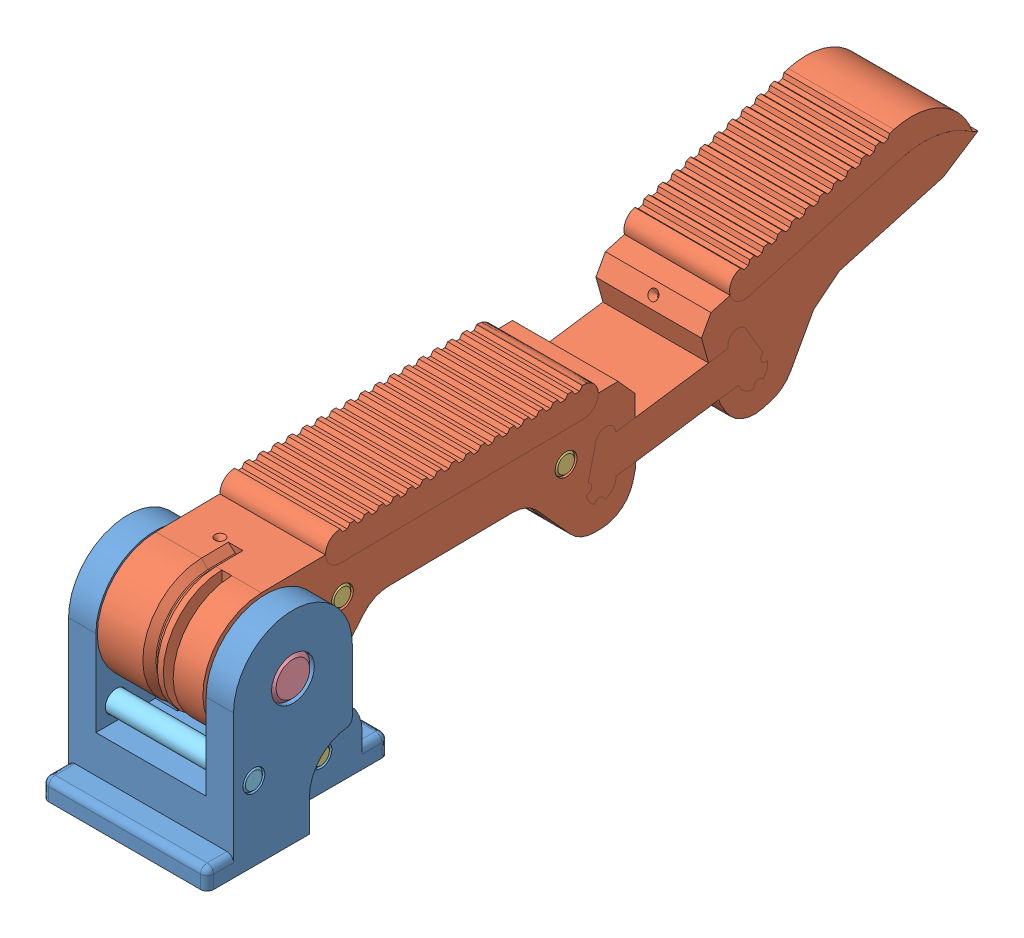
SolidWorks assembly block_finger_pf_t, configuration Default. Lengths in mm.
Overall size (25.4 45.69 121.76).
10 component instances, 8 part files, 18 mates.
Components (placement in the parent):
- c1_t-1: c1_t [Default] at origin size (25 30.67 32)
- t_pf-1: t_pf [Default] at (-0.15 21.67 -14.7858) x (1 0 0) z (0 -0.013363 0.999911) size (16 29.93 117.65)
- 98381A472 D1-8 L5-8-1: 98381A472 D1-8 L5-8 [98381A472] at (-0.0875 23.995 -26.9308) size (15.88 3.17 3.17)
- 98381A472 D1-8 L5-8-2: 98381A472 D1-8 L5-8 [98381A472] at (-0.0875 24.448 -60.8289) size (15.88 3.17 3.17)
- 98381A542 D1-4 L1-1: 98381A542 D1-4 L1 [98381A542] at (-0.2 21.67 -14.7858) size (25.4 6.35 6.35)
- 98381A475 D1-8 L1-1: 98381A475 D1-8 L1 [98381A475] at (-0.2 11.2575 -8.8732) size (25.4 3.17 3.17)
- 98381A472 D1-8 L5-8-3: 98381A472 D1-8 L5-8 [98381A472] at (0.0625 4.925 -23.535) size (15.88 3.17 3.17)
- 93365A120 4-40 insert-1: 93365A120 4-40 insert [93365A120] at (-0.15 27.5639 -100.2943) x (1 0 0) z (0 0.622567 -0.782567) size (4.37 3.82 4.37)
- 91253A106 4-40 L1-4 countersunk-1: 91253A106 4-40 L1-4 countersunk [91253A106] at (-0.15 25.9039 -101.6148) x (1 0 0) z (0 -0.782567 -0.622567) size (6.48 6.48 6.63)
- 3434T31 - nylon pulley-1: 3434T31 - nylon pulley [Default] at (-0.15 4.925 -23.535) x (0 -0.840446 -0.541896) z (0 -0.541896 0.840446) size (9.5 2.4 9.5)
Mates (geometry in assembly coordinates):
- Concentric1: concentric: cylinder of c1_t-1 through (-12.5 21.67 -14.7858) axis (1 0 0) radius 3.25; cylinder of 98381A542 D1-4 L1-1 through (-12.9 21.67 -14.7858) axis (1 0 0) radius 3.175
- Coincident1: coincident: plane of c1_t-1 through (12.5 21.67 -14.7858) normal (1 0 0); plane of 98381A542 D1-4 L1-1 through (12.5 21.67 -14.7858) normal (1 0 0)
- Concentric2: concentric: cylinder of t_pf-1 through (-8.15 21.67 -14.7858) axis (1 0 0) radius 3.35; cylinder of 98381A542 D1-4 L1-1 through (-12.9 21.67 -14.7858) axis (1 0 0) radius 3.175
- Distance1: distance = 0.2 mm: plane of c1_t-1 through (-8.35 21.67 -14.7858) normal (1 0 0); plane of t_pf-1 through (-8.15 21.67 -14.7858) normal (-1 0 0)
- Concentric3: concentric: cylinder of t_pf-1 through (-8.15 23.995 -26.9308) axis (1 0 0) radius 1.6625; cylinder of 98381A472 D1-8 L5-8-1 through (-8.025 23.995 -26.9308) axis (1 0 0) radius 1.5875
- Coincident3: coincident: plane of t_pf-1 through (7.85 21.67 -14.7858) normal (1 0 0); plane of 98381A472 D1-8 L5-8-1 through (7.85 23.995 -26.9308) normal (1 0 0)
- Concentric4: concentric: cylinder of t_pf-1 through (-8.15 24.448 -60.8289) axis (1 0 0) radius 1.6625; cylinder of 98381A472 D1-8 L5-8-2 through (-8.025 24.448 -60.8289) axis (1 0 0) radius 1.5875
- Coincident4: coincident: plane of t_pf-1 through (7.85 21.67 -14.7858) normal (1 0 0); plane of 98381A472 D1-8 L5-8-2 through (7.85 24.448 -60.8289) normal (1 0 0)
- Concentric5: concentric: cylinder of c1_t-1 through (-12.5 4.925 -23.535) axis (1 0 0) radius 1.6625; cylinder of 98381A472 D1-8 L5-8-3 through (-7.875 4.925 -23.535) axis (1 0 0) radius 1.5875
- Coincident5: coincident: plane of c1_t-1 through (8 4.925 -23.535) normal (1 0 0); plane of 98381A472 D1-8 L5-8-3 through (8 4.925 -23.535) normal (1 0 0)
- Concentric6: concentric: cylinder of c1_t-1 through (-12.5 11.2575 -8.8732) axis (1 0 0) radius 1.6625; cylinder of 98381A475 D1-8 L1-1 through (-12.9 11.2575 -8.8732) axis (1 0 0) radius 1.5875
- Coincident6: coincident: plane of c1_t-1 through (12.5 21.67 -14.7858) normal (1 0 0); plane of 98381A475 D1-8 L1-1 through (12.5 11.2575 -8.8732) normal (1 0 0)
- Concentric7: concentric: cylinder of t_pf-1 through (-0.15 31.0854 -97.4927) axis (0 -0.782567 -0.622567) radius 1.85; circle of 93365A120 4-40 insert-1
- Coincident7: coincident: plane of t_pf-1 through (-13.15 26.0075 -98.3378) normal (0 -0.782567 -0.622567); plane of 93365A120 4-40 insert-1 through (-0.15 27.5639 -100.2943) normal (0 -0.782567 -0.622567)
- Concentric8: concentric: circle of 93365A120 4-40 insert-1; circle of 91253A106 4-40 L1-4 countersunk-1
- Coincident8: coincident: circle of 93365A120 4-40 insert-1; cone of 91253A106 4-40 L1-4 countersunk-1 through (-0.15 27.5537 -100.3023) axis (0 0.782567 0.622567)
- Concentric9: concentric: cylinder of 98381A472 D1-8 L5-8-3 through (-7.875 4.925 -23.535) axis (1 0 0) radius 1.5875; cylinder of 3434T31 - nylon pulley-1 through (-0.15 4.925 -23.535) axis (-1 0 0) radius 1.5
- Distance2: distance = 0.2 mm: plane of c1_t-1 through (-1.55 4.925 -23.535) normal (1 0 0); plane of 3434T31 - nylon pulley-1 through (-1.35 3.6643 -24.3478) normal (-1 0 0)
